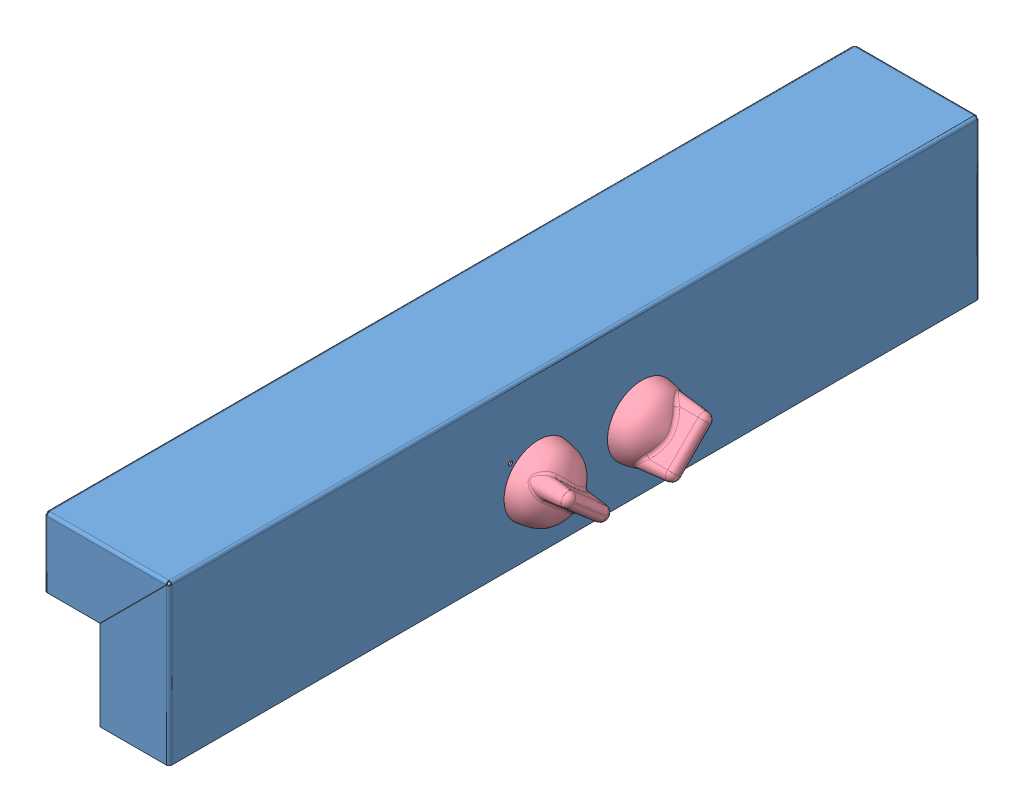
SolidWorks assembly Control_Panel, configuration Default. Lengths in mm.
Overall size (141.73 125.52 596.9).
7 component instances, 4 part files, 3 mates.
Components (placement in the parent):
- control_panel-1: control_panel [Default] at origin
- Valve Assembly-1: Valve Assembly [Default] at (-29.591 -58.1439 0) size (127 125.52 202.58)
  - Valve Mixer 1-10-1: Valve Mixer 1-10 [Default] at origin
  - Control Shaft-3: Control Shaft [Default] at (3.175 0 38.1) x (1 0 0) z (0 -0.078346 0.996926)
  - Control Shaft-4: Control Shaft [Default] at (3.175 0 -38.1) x (1 0 0) z (0 -0.999998 -0.002065)
  - Lofted Control Knob-1: Lofted Control Knob [Default] at (41.275 0 38.1) x (0 0.649535 0.760332) z (0 0.760332 -0.649535)
  - Lofted Control Knob-2: Lofted Control Knob [Default] at (41.275 0 -38.1) x (0 -0.708566 0.705645) z (0 0.705645 0.708566)
Mates (geometry in assembly coordinates):
- Coincident1: coincident anti-aligned: plane of control_panel-1 through (-1.016 0 298.45) normal (-1 0 0); plane of Valve Assembly-1/Valve Mixer 1-10-1 through (-1.016 -58.1439 38.1) normal (1 0 0)
- Concentric1: concentric anti-aligned: cylinder of control_panel-1 through (-1.016 -58.1439 38.1) axis (1 0 0) radius 6.35; cylinder of Valve Assembly-1/Control Shaft-3 through (30.734 -58.1439 38.1) axis (-1 0 0) radius 5.5563
- Perpendicular1: perpendicular: plane of control_panel-1 through (-1.016 0 298.45) normal (-1 0 0); plane of Valve Assembly-1 through (-29.591 -58.1439 0) normal (0 0 1)
